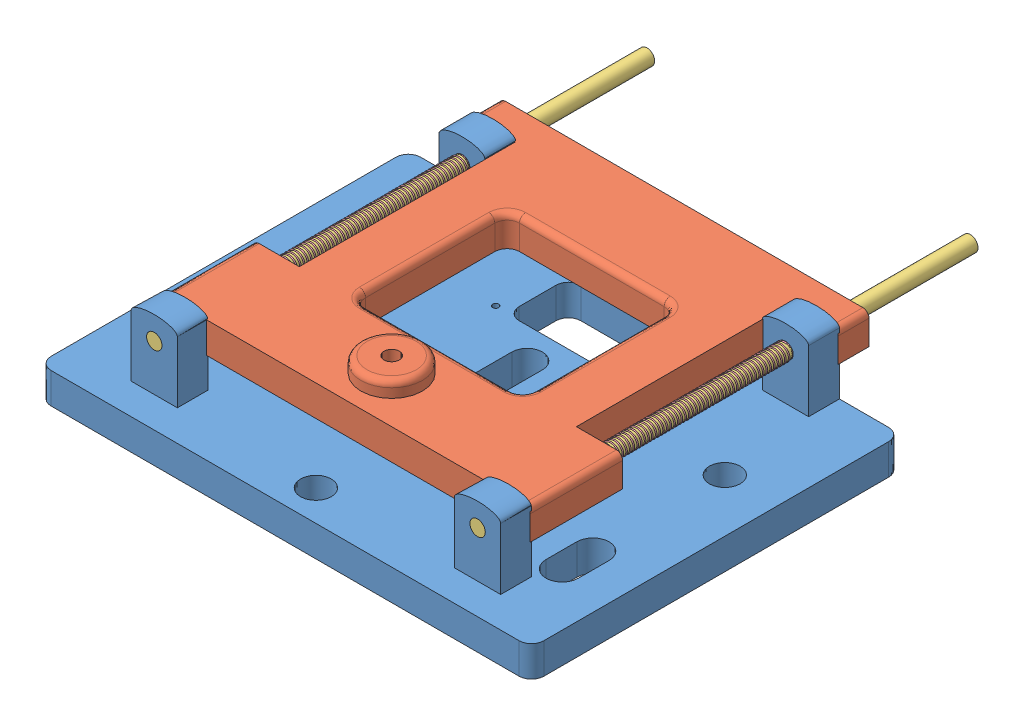
SolidWorks assembly Drawing Mount Assembly, configuration Default. Lengths in mm.
Overall size (101.6 22.23 107.95).
6 component instances, 4 part files, 14 mates.
Components (placement in the parent):
- Drawing Mount-1: Drawing Mount [Default] at (39.6439 44.0201 83.1941) size (101.6 21.18 76.2)
- Drawing mount 2-1: Drawing mount 2 [Default] at (39.7074 56.7201 62.1343) size (76.2 9.53 69.85)
- 0.125 Dowel pin-1: 0.125 Dowel pin [Default] at (6.3064 59.8951 0.6441) x (0.801473 -0.598031 0) z (0 0 1) size (3.17 3.17 101.6)
- 0.125 Dowel pin-2: 0.125 Dowel pin [Default] at (72.9814 59.8951 0.6441) x (0.816688 0.577079 0) z (0 0 1) size (3.17 3.17 101.6)
- Spring-1: Spring [Default] at (6.3064 59.8951 38.9981) x (0.94588 -0.324516 0) z (-0.324516 -0.94588 0) size (3.43 38.61 3.96)
- Spring-2: Spring [Default] at (72.9814 59.8951 38.9981) x (-0.31762 -0.948218 0) z (-0.948218 0.31762 0) size (3.43 38.61 3.96)
Mates (geometry in assembly coordinates):
- Parallel1: parallel anti-aligned: plane of Drawing Mount-1 through (1.5439 63.0701 95.8941) normal (0 0 -1); plane of Drawing mount 2-1 through (77.8074 63.0701 96.2144) normal (0 0 1)
- Concentric1: concentric anti-aligned: circle of Drawing Mount-1; circle of Drawing mount 2-1
- Parallel2: parallel aligned: plane of Drawing Mount-1 through (68.2189 63.0701 38.7441) normal (0 0 1); plane of Drawing mount 2-1 through (77.8074 63.0701 32.7144) normal (0 0 1)
- Parallel3: parallel anti-aligned: plane of Drawing Mount-1 through (39.6439 50.3701 83.1941) normal (0 1 0); plane of Drawing mount 2-1 through (39.7074 56.7201 62.1343) normal (0 -1 0)
- Concentric2: concentric anti-aligned: cylinder of Drawing Mount-1 through (6.3064 59.8951 32.3941) axis (0 0 1) radius 1.5875; cylinder of 0.125 Dowel pin-1 through (6.3064 59.8951 102.2441) axis (0 0 -1) radius 1.5875
- Coincident5: coincident aligned: plane of Drawing Mount-1 through (1.5439 63.0701 102.2441) normal (0 0 1); plane of 0.125 Dowel pin-1 through (6.3064 59.8951 102.2441) normal (0 0 1)
- Concentric3: concentric anti-aligned: cylinder of Drawing Mount-1 through (72.9814 59.8951 32.3941) axis (0 0 1) radius 1.5875; cylinder of 0.125 Dowel pin-2 through (72.9814 59.8951 102.2441) axis (0 0 -1) radius 1.5875
- Coincident6: coincident aligned: plane of Drawing Mount-1 through (77.7439 63.0701 102.2441) normal (0 0 1); plane of 0.125 Dowel pin-2 through (72.9814 59.8951 102.2441) normal (0 0 1)
- Coincident7: coincident aligned: plane of Drawing Mount-1 through (1.5439 63.0701 102.2441) normal (0 0 1); plane of 0.125 Dowel pin-1 through (6.3064 59.8951 102.2441) normal (0 0 1)
- Coincident9: coincident aligned: plane of Drawing Mount-1 through (77.7439 63.0701 102.2441) normal (0 0 1); plane of 0.125 Dowel pin-2 through (72.9814 59.8951 102.2441) normal (0 0 1)
- Concentric4: concentric aligned: circle of 0.125 Dowel pin-1; circle of Spring-1
- Coincident10: coincident aligned: plane of Drawing Mount-1 through (1.5439 63.0701 38.7441) normal (0 0 1); circle of Spring-1
- Concentric5: concentric aligned: circle of 0.125 Dowel pin-2; circle of Spring-2
- Coincident11: coincident aligned: plane of Drawing Mount-1 through (68.2189 63.0701 38.7441) normal (0 0 1); circle of Spring-2
